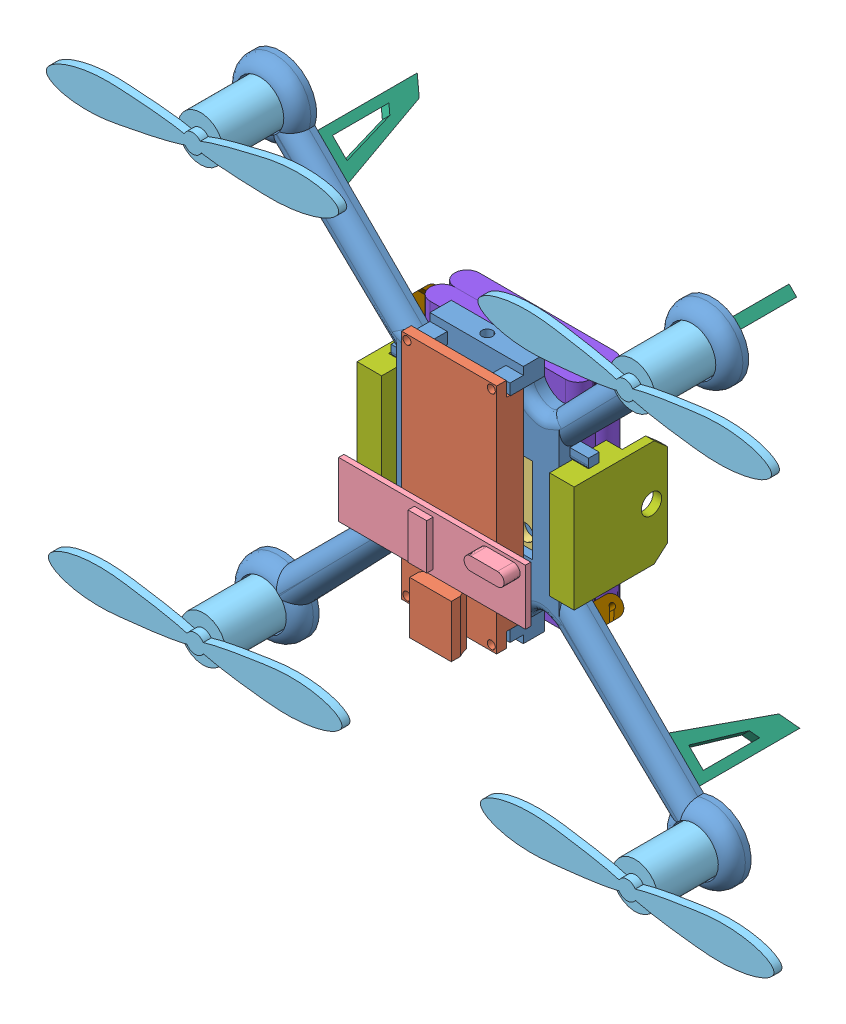
SolidWorks assembly drone, configuration Default. Lengths in mm.
Overall size (136.81 94.92 36.8).
20 component instances, 9 part files, 37 mates.
Components (placement in the parent):
- drone1-1: drone1 [Default] at (37.8927 42.6997 72.3519) size (94.92 94.92 6.5)
- drone_nano-1: drone_nano [Default] at (37.7427 42.7746 79.5519) x (0 -1 0) z (0 0 1) size (45.5 17.8 8.5)
- drone_mpu-1: drone_mpu [Default] at (37.5927 42.6997 74.8519) x (0 1 0) z (0 0 -1) size (16 20.4 1.5)
- drone_reciever-1: drone_reciever [Default] at (39.3364 37.7445 85.1546) size (35 10.4 4)
- drone_fan-1: drone_fan [Default] at (-2.3486 1.9896 72.3519) size (55.13 8.5 16.5)
- drone_fan-2: drone_fan [Default] at (78.6028 2.4583 72.3519) size (55.13 8.5 16.5)
- drone_fan-3: drone_fan [Default] at (78.1341 83.4098 72.3519) x (0.999906 -0.013699 0) z (0 0 1) size (55.13 8.5 16.5)
- drone_fan-4: drone_fan [Default] at (-2.8174 82.941 72.3519) x (0.996492 0.083693 0) z (0 0 1) size (55.13 8.5 16.5)
- DRONE_LEG-1: DRONE_LEG [Default] at (7.2795 14.4748 72.3519) x (0.707107 0.707107 0) z (0.707107 -0.707107 0) size (8.5 21.5 2)
- DRONE_LEG-2: DRONE_LEG [Default] at (8.7696 72.8834 72.3519) x (0.707107 -0.707107 0) z (-0.707107 -0.707107 0) size (8.5 21.5 2)
- DRONE_LEG-3: DRONE_LEG [Default] at (67.0158 12.9847 72.3519) x (-0.707107 0.707107 0) z (0.707107 0.707107 0) size (8.5 21.5 2)
- DRONE_LEG-4: DRONE_LEG [Default] at (67.8421 72.0572 72.3519) x (-0.707107 -0.707107 0) z (-0.707107 0.707107 0) size (8.5 21.5 2)
- drone_driver-1: drone_driver [Default] at (58.4615 44.0497 68.6519) x (0 0 1) z (-1 0 0) size (17.5 20 4.6)
- drone_driver-2: drone_driver [Default] at (17.7927 41.3497 68.6519) x (0 0 1) z (1 0 0) size (17.5 20 4.6)
- drone_battery-1: drone_battery [Default] at (35.9873 63.0641 70.0519) x (0 -1 0) z (-1 0 0) size (41 4.6 30)
- drone_battery-2: drone_battery [Default] at (35.9873 63.0641 65.4519) x (0 -1 0) z (-1 0 0) size (41 4.6 30)
- drone_battery_holder-1: drone_battery_holder [Default] at (54.0921 25.0861 71.3519) x (0.707107 0.707107 0) z (-0.707107 0.707107 0) size (2 7.25 3.5)
- drone_battery_holder-2: drone_battery_holder [Default] at (20.2792 26.5003 71.3519) x (0.707107 -0.707107 0) z (0.707107 0.707107 0) size (2 7.25 3.5)
- drone_battery_holder-3: drone_battery_holder [Default] at (21.6934 60.3133 71.3519) x (-0.707107 -0.707107 0) z (0.707107 -0.707107 0) size (2 7.25 3.5)
- drone_battery_holder-4: drone_battery_holder [Default] at (55.5063 58.899 71.3519) x (-0.707107 0.707107 0) z (-0.707107 -0.707107 0) size (2 7.25 3.5)
Mates (geometry in assembly coordinates):
- Coincident3: coincident: plane of drone1-1 through (37.8927 42.6997 76.3519) normal (0 0 1); plane of drone_nano-1 through (37.7427 42.7746 76.3519) normal (0 0 -1)
- Coincident4: coincident: plane of drone1-1 through (46.6427 42.6997 76.3519) normal (1 0 0); plane of drone_nano-1 through (46.6427 42.7746 81.3519) normal (1 0 0)
- Parallel2: parallel: plane of drone1-1 through (37.8927 65.1997 76.3519) normal (0 1 0); plane of drone_nano-1 through (37.7427 64.5246 81.3519) normal (0 1 0)
- Coincident13: coincident: plane of drone1-1 through (37.8927 42.6997 73.3519) normal (0 0 1); plane of drone_mpu-1 through (37.5927 42.6997 73.3519) normal (0 0 -1)
- Coincident14: coincident: plane of drone1-1 through (27.3927 34.6997 73.3519) normal (1 0 0); plane of drone_mpu-1 through (27.3927 50.6997 73.3519) normal (-1 0 0)
- Coincident15: coincident: plane of drone1-1 through (48.3927 34.6997 73.3519) normal (0 1 0); plane of drone_mpu-1 through (27.3927 34.6997 73.3519) normal (0 -1 0)
- Concentric1: concentric: cylinder of drone1-1 through (-2.3486 1.9896 76.3519) axis (0 0 -1) radius 4.5; cylinder of drone_fan-1 through (-2.3486 1.9896 87.3519) axis (0 0 -1) radius 4.25
- Coincident16: coincident: plane of drone1-1 through (37.8927 42.6997 72.3519) normal (0 0 -1); plane of drone_fan-1 through (-2.3486 1.9896 72.3519) normal (0 0 -1)
- Coincident17: coincident: plane of drone1-1 through (37.8927 42.6997 72.3519) normal (0 0 -1); plane of drone_fan-3 through (78.1341 83.4098 72.3519) normal (0 0 -1)
- Coincident18: coincident: plane of drone1-1 through (37.8927 42.6997 72.3519) normal (0 0 -1); circle of drone_fan-4
- Coincident19: coincident: plane of drone1-1 through (37.8927 42.6997 72.3519) normal (0 0 -1); plane of drone_fan-2 through (78.6028 2.4583 72.3519) normal (0 0 -1)
- Concentric2: concentric: circle of drone1-1; circle of drone_fan-2
- Concentric3: concentric: circle of drone1-1; circle of drone_fan-3
- Concentric4: concentric: circle of drone1-1; circle of drone_fan-4
- Coincident20: coincident: plane of drone1-1 through (37.8927 42.6997 73.8519) normal (0 0 -1); plane of DRONE_LEG-1 through (6.926 11.2928 73.8519) normal (0 0 1)
- Coincident21: coincident: plane of drone1-1 through (3.8775 9.3915 73.8519) normal (0.707107 -0.707107 0); plane of DRONE_LEG-1 through (6.3524 11.8664 72.3519) normal (-0.707107 0.707107 0)
- Coincident27: coincident: line of drone1-1 through (3.2896 75.8886 72.3519) axis (0.707107 0.707107 0); plane of DRONE_LEG-2 through (3.1128 75.7119 73.8519) normal (-0.707107 0.707107 0)
- Coincident28: coincident: line of drone1-1 through (6.118 73.7673 72.3519) axis (-0.707107 0.707107 0); plane of DRONE_LEG-2 through (6.118 73.7673 72.3519) normal (-0.707107 -0.707107 0)
- Coincident30: coincident: plane of drone1-1 through (37.8927 42.6997 73.8519) normal (0 0 -1); plane of DRONE_LEG-2 through (5.5877 73.237 73.8519) normal (0 0 1)
- Coincident31: coincident: plane of drone1-1 through (37.8927 42.6997 73.8519) normal (0 0 -1); plane of DRONE_LEG-4 through (68.1957 75.2391 73.8519) normal (0 0 1)
- Coincident36: coincident: line of drone1-1 through (70.8473 77.5372 72.3519) axis (0.707107 -0.707107 0); plane of DRONE_LEG-4 through (70.6706 77.714 73.8519) normal (0.707107 0.707107 0)
- Coincident37: coincident: line of drone1-1 through (71.908 76.4766 72.3519) axis (-0.707107 -0.707107 0); plane of DRONE_LEG-4 through (69.4331 74.0017 72.3519) normal (0.707107 -0.707107 0)
- Coincident38: coincident: line of drone1-1 through (69.6675 12.1008 72.3519) axis (0.707107 -0.707107 0); plane of DRONE_LEG-3 through (69.6675 12.1008 72.3519) normal (0.707107 0.707107 0)
- Coincident39: coincident: plane of drone1-1 through (37.8927 42.6997 73.8519) normal (0 0 -1); plane of DRONE_LEG-3 through (70.1978 12.6311 73.8519) normal (0 0 1)
- Coincident40: coincident: plane of drone1-1 through (5.9988 12.22 73.8519) normal (-0.707107 -0.707107 0); plane of DRONE_LEG-1 through (6.926 11.2928 72.3519) normal (0.707107 0.707107 0)
- Coincident42: coincident: plane of drone1-1 through (68.6068 11.0401 73.8519) normal (0.707107 -0.707107 0); plane of DRONE_LEG-3 through (70.1978 12.6311 72.3519) normal (-0.707107 0.707107 0)
- Coincident47: coincident: circle of drone_driver-1; cylinder of drone_driver-2 through (19.3927 42.6997 64.1519) axis (-1 0 0) radius 1.9
- Coincident49: coincident: plane of drone1-1 through (37.8927 42.6997 72.3519) normal (0 0 -1); plane of drone_battery-1 through (25.1737 22.0641 72.3519) normal (0 0 1)
- Perpendicular1: perpendicular: line of drone_driver-2 through (22.3927 32.6997 68.0519) axis (0 1 0); line of drone_battery-1 through (25.1737 22.0641 67.7519) axis (1 0 0)
- Coincident55: coincident: plane of drone_battery-1 through (25.1737 22.0641 67.7519) normal (0 0 -1); plane of drone_battery-2 through (25.1737 22.0641 67.7519) normal (0 0 1)
- Coincident57: coincident: line of drone_battery-1 through (25.1737 22.0641 67.7519) axis (0 1 0); line of drone_battery-2 through (25.1737 22.0641 67.7519) axis (0 1 0)
- Coincident58: coincident: plane of drone_battery-1 through (25.1737 63.0641 70.0519) normal (0 1 0); plane of drone_battery-2 through (25.1737 63.0641 65.4519) normal (0 1 0)
- Coincident59: coincident: plane of drone1-1 through (55.1528 24.0254 73.8519) normal (0.707107 0.707107 0); plane of drone_battery_holder-1 through (54.0921 25.0861 71.3519) normal (-0.707107 -0.707107 0)
- Coincident62: coincident: plane of drone1-1 through (56.567 25.4397 73.8519) normal (-0.707107 0.707107 0); plane of drone_battery_holder-1 through (56.567 25.4397 71.3519) normal (0.707107 -0.707107 0)
- Coincident63: coincident: plane of drone1-1 through (37.8927 42.6997 73.8519) normal (0 0 -1); plane of drone_battery_holder-1 through (55.5063 26.5003 73.8519) normal (0 0 1)
- Concentric5: concentric: cylinder of drone1-1 through (19.8615 52.6997 73.3519) axis (1 0 0) radius 1; cylinder of drone_driver-1 through (56.8615 52.6997 73.3519) axis (-1 0 0) radius 1
- Coincident64: coincident: plane of drone1-1 through (56.8615 52.6997 73.3519) normal (1 0 0); line of drone_driver-1 through (56.8615 52.6997 72.3519) axis (0 0 1)
